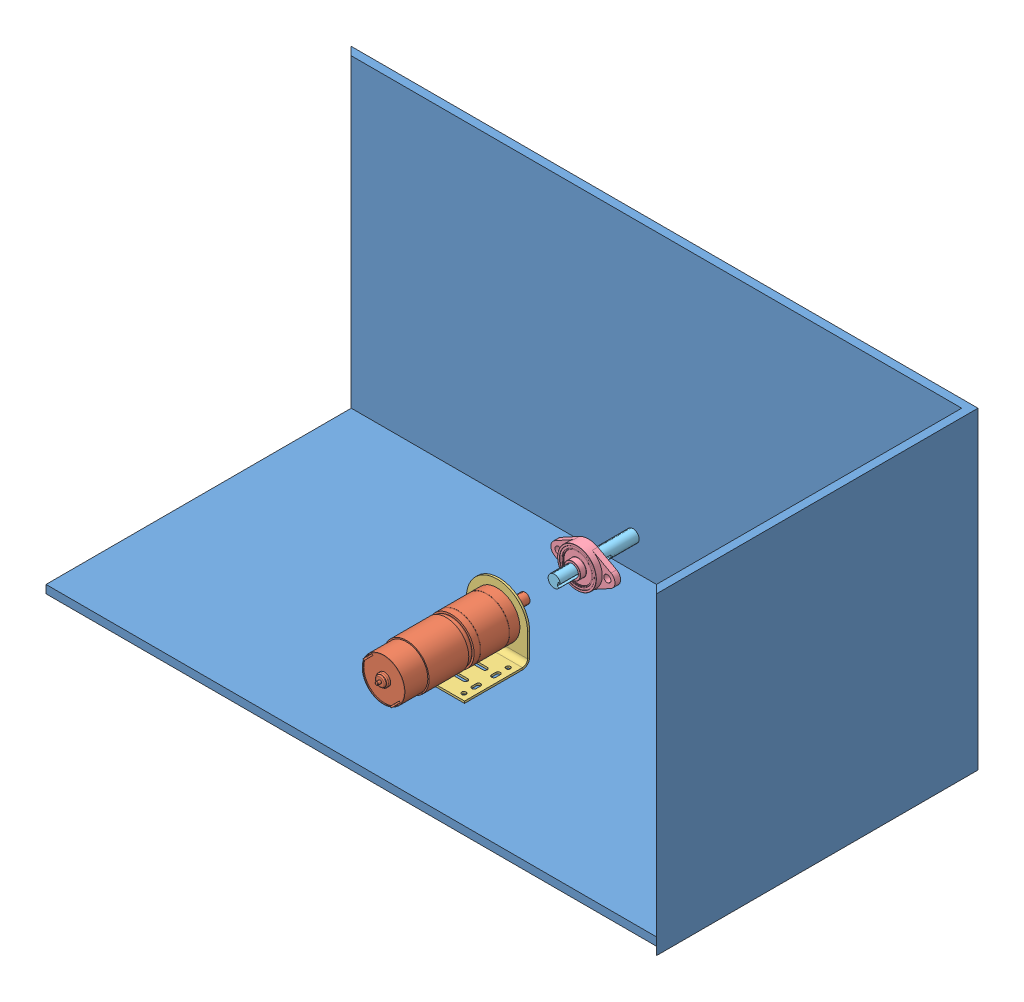
SolidWorks assembly moter in box assemly, configuration Default. Lengths in mm.
Overall size (616 308 484.54).
5 component instances, 5 part files, 8 mates.
Components (placement in the parent):
- box-1: box [Default] at (214.7869 209.4239 556.9442) size (616 308 316)
- Motor DC PG45-1: Motor DC PG45 [Default] at (191.7473 247.4239 652.1282) x (0.707107 0.707107 0) z (-0.707107 0.707107 0) size (45 146.01 45)
- Mounting Bracket Motor DC PG45 Orange-1: Mounting Bracket Motor DC PG45 Orange [Default] at (213.3361 243.9192 540.6282) x (-1 0 0) z (0 0 -1) size (60 60 63.93)
- KFL001 block flange ball bearing 12 diameter shaft-1: KFL001 block flange ball bearing 12 diameter shaft [Default] at (191.7473 247.4239 450.682) x (0 1 0) z (1 0 0) size (38 16 63)
- wheel shaft-1: wheel shaft [Default] at (191.7473 247.4239 230.4015) x (0.256992 0.966413 0) z (0.966413 -0.256992 0) size (12 254 12)
Mates (geometry in assembly coordinates):
- Concentric1: concentric aligned: circle of Motor DC PG45-1; circle of Mounting Bracket Motor DC PG45 Orange-1
- Coincident1: coincident aligned: plane of Motor DC PG45-1 through (191.7473 247.4239 540.6282) normal (0 0 -1); circle of Mounting Bracket Motor DC PG45 Orange-1
- Parallel1: parallel anti-aligned: line of box-1 through (-85.2131 217.4239 406.9442) axis (0 0 1); line of Mounting Bracket Motor DC PG45 Orange-1 through (161.7473 217.4239 602.5582) axis (0 0 -1)
- Coincident2: coincident anti-aligned: plane of box-1 through (214.7869 217.4239 556.9442) normal (0 1 0); plane of Mounting Bracket Motor DC PG45 Orange-1 through (213.3361 217.4239 540.6282) normal (0 -1 0)
- Coincident3: coincident anti-aligned: plane of box-1 through (214.7869 217.4239 556.9442) normal (0 1 0); plane of Mounting Bracket Motor DC PG45 Orange-1 through (213.3361 217.4239 540.6282) normal (0 -1 0)
- Concentric2: concentric aligned: circle of Motor DC PG45-1; circle of Mounting Bracket Motor DC PG45 Orange-1
- Concentric3: concentric anti-aligned: circle of Motor DC PG45-1; circle of KFL001 block flange ball bearing 12 diameter shaft-1
- Concentric4: concentric aligned: circle of KFL001 block flange ball bearing 12 diameter shaft-1; circle of wheel shaft-1
